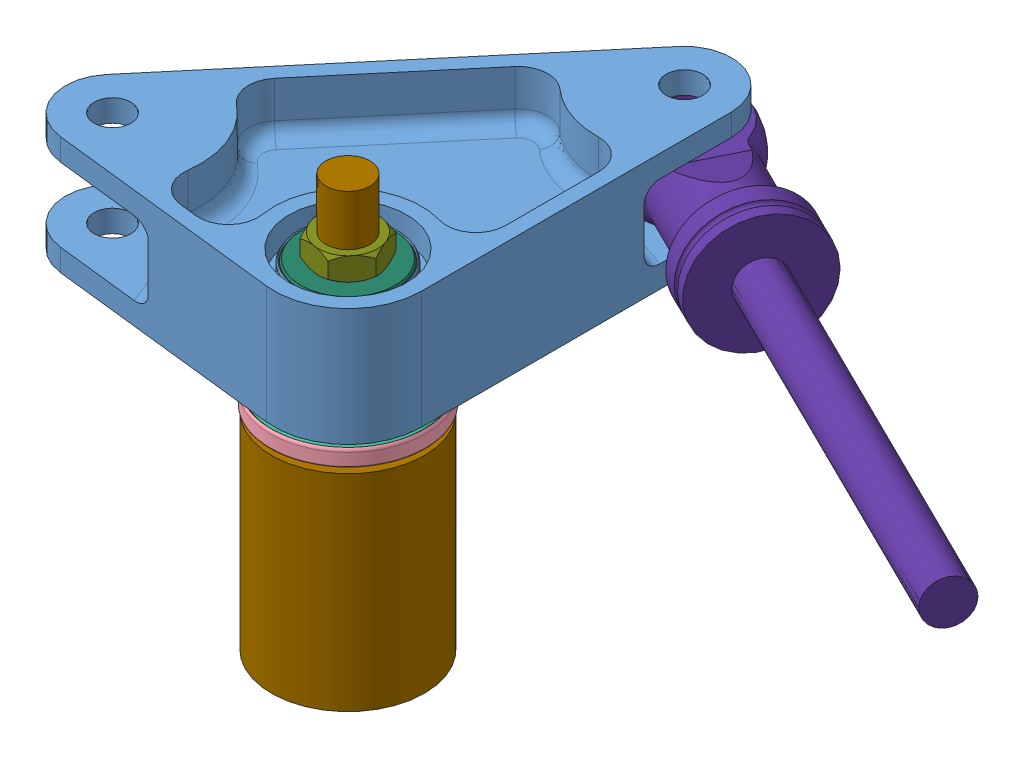
SolidWorks assembly Bell Crank Assembly, configuration Default. Lengths in mm.
Overall size (184.72 88.9 146.21).
20 component instances, 18 part files, 16 mates.
Components (placement in the parent):
- Bell Crank-1: Bell Crank [Default] at origin size (76.83 25.4 92.98)
- combined_bearing_-_rax_718-1: combined_bearing_-_rax_718 [Default] at (0 -16.9 0) x (0 1 0) z (0.807058 0 0.590472) size (18.2 33.5 33.5)
  - combined_bearing_-_rax_718_01-1: combined_bearing_-_rax_718_01 [Default] at origin size (13.9 21.05 21.05)
  - combined_bearing_-_rax_718_02-1: combined_bearing_-_rax_718_02 [Default] at origin size (1.27 30.9 30.9)
  - combined_bearing_-_rax_718_03-1: combined_bearing_-_rax_718_03 [Default] at origin size (3.62 33.5 33.5)
  - combined_bearing_-_rax_718_04-1: combined_bearing_-_rax_718_04 [Default] at origin size (0.66 31.22 31.22)
  - combined_bearing_-_rax_718_05-1: combined_bearing_-_rax_718_05 [Default] at origin size (17.38 32.86 32.86)
  - combined_bearing_-_rax_718_06-1: combined_bearing_-_rax_718_06 [Default] at origin size (11.81 22.36 22.36)
  - combined_bearing_-_rax_718_07-1: combined_bearing_-_rax_718_07 [Default] at origin size (2 28.7 28.7)
- Bell Crank Pivot-1: Bell Crank Pivot [Default] at (0 -55.8 0) x (0 -1 0) z (-0.999995 0 0.003263) size (88.9 33.02 33.02)
- thrust_plate_cp_18_30-2: thrust_plate_cp_18_30 [Default] at (0 -16.9 0) x (0 -1 0) z (0.103205 0 -0.99466) size (0.8 29.5 29.5)
- thrust_plate_cp_10_22-1: thrust_plate_cp_10_22 [Default] at (0 8.1025 0) x (0 -1 0) z (0.860646 0 0.509204) size (0.8 21.5 21.5)
- needles_thrust_bearing_ax_10_22-1: needles_thrust_bearing_ax_10_22 [Default] at (0 10.9025 0) x (0 -1 0) z (-0.277222 0 0.960806) size (2.8 22 22)
  - needles_thrust_bearing_ax_10_22_01-1: needles_thrust_bearing_ax_10_22_01 [Default] at origin size (1.2 20.42 20.42)
  - needles_thrust_bearing_ax_10_22_02-1: needles_thrust_bearing_ax_10_22_02 [Default] at origin size (2 18.6 18.6)
  - needles_thrust_bearing_ax_10_22_03-1: needles_thrust_bearing_ax_10_22_03 [Default] at origin size (2.3 22 22)
  - needles_thrust_bearing_ax_10_22_04-1: needles_thrust_bearing_ax_10_22_04 [Default] at origin size (0.8 21.21 21.21)
- Hex Jam Nut_AI-1: Hex Jam Nut_AI [HJNUT 0.3125-24-D-N] at (0 10.9025 0) x (-0.160393 0 0.987053) z (0 -1 0) size (12.7 14.66 4.95)
- Penske7800_Shaft-1: Penske7800_Shaft [Default] at (5.6801 0 -66.9424) x (0 -1 0) z (0.44263 0 -0.896705) size (25.4 138.11 25.4)
- Inner_Ring_IM_13_18_6.4-2: Inner_Ring_IM_13_18_6.4 [Default] at (0 -8.5 0) x (0 -1 0) z (-0.346095 0 0.938199) size (18.4 18 18)
Mates (geometry in assembly coordinates):
- Concentric1: concentric aligned: cylinder of Bell Crank-1 through (0 2.54 0) axis (0 -1 0) radius 12; cylinder of combined_bearing_-_rax_718-1/combined_bearing_-_rax_718_05-1 through (0 -16.9 0) axis (0 -1 0) radius 12
- Coincident1: coincident anti-aligned: plane of Bell Crank-1 through (-50.8 -12.7 0) normal (0 -1 0); plane of combined_bearing_-_rax_718-1/combined_bearing_-_rax_718_05-1 through (-9.2173 -12.7 12.5982) normal (0 1 0)
- Concentric2: concentric aligned: cylinder of Bell Crank-1 through (0 2.54 0) axis (0 -1 0) radius 12; cylinder of Bell Crank Pivot-1 through (0 -55.8 0) axis (0 -1 0) radius 6.5
- Concentric3: concentric anti-aligned: cylinder of Bell Crank-1 through (0 2.54 0) axis (0 -1 0) radius 12; cylinder of thrust_plate_cp_18_30-2 through (0 -17.7 0) axis (0 1 0) radius 9
- Tangent1: tangent anti-aligned: cylinder of combined_bearing_-_rax_718-1/combined_bearing_-_rax_718_07-1 through (-10.0075 -15.9 -7.3219) axis (0.807058 0 0.590472) radius 1; plane of thrust_plate_cp_18_30-2 through (0 -16.9 0) normal (0 1 0)
- Coincident2: coincident anti-aligned: plane of Bell Crank Pivot-1 through (16.5099 -17.7 -0.0539) normal (0 1 0); plane of thrust_plate_cp_18_30-2 through (0 -17.7 0) normal (0 -1 0)
- Concentric6: concentric anti-aligned: cylinder of Bell Crank Pivot-1 through (0 -55.8 0) axis (0 -1 0) radius 4.7625; cylinder of thrust_plate_cp_10_22-1 through (0 8.1025 0) axis (0 1 0) radius 5
- Coincident4: coincident anti-aligned: plane of Bell Crank-1 through (0 7.3025 0) normal (0 1 0); plane of thrust_plate_cp_10_22-1 through (2.546 7.3025 -4.3032) normal (0 -1 0)
- Concentric7: concentric anti-aligned: cylinder of Bell Crank Pivot-1 through (0 -55.8 0) axis (0 -1 0) radius 4.7625; cylinder of needles_thrust_bearing_ax_10_22-1/needles_thrust_bearing_ax_10_22_04-1 through (0 10.9025 0) axis (0 1 0) radius 5
- Tangent3: tangent anti-aligned: plane of thrust_plate_cp_10_22-1 through (5.4739 8.1025 -9.2519) normal (0 1 0); cylinder of needles_thrust_bearing_ax_10_22-1/needles_thrust_bearing_ax_10_22_02-1 through (-7.3502 9.1025 -2.1207) axis (0.960806 0 0.277222) radius 1
- Concentric8: concentric aligned: cylinder of Bell Crank Pivot-1 through (0 -55.8 0) axis (0 -1 0) radius 4.7625; cylinder of Hex Jam Nut_AI-1 through (0 15.8555 0) axis (0 -1 0) radius 3.4544
- Coincident5: coincident anti-aligned: plane of needles_thrust_bearing_ax_10_22-1/needles_thrust_bearing_ax_10_22_04-1 through (9.7446 10.9025 2.8116) normal (0 1 0); plane of Hex Jam Nut_AI-1 through (-7.2374 10.9025 -1.1761) normal (0 -1 0)
- Concentric11: concentric anti-aligned: circle of Bell Crank-1; cylinder of Penske7800_Shaft-1 through (5.6801 12.7 -66.9424) axis (0 -1 0) radius 7.9375
- Distance2: distance = 1.5875 mm anti-aligned: plane of Bell Crank-1 through (28.0482 7.9375 -72.6581) normal (0 -1 0); plane of Penske7800_Shaft-1 through (39.0513 6.35 -36.3069) normal (0 1 0)
- Tangent4: tangent: plane of Bell Crank Pivot-1 through (16.5099 -17.7 -0.0539) normal (0 1 0); torus of Inner_Ring_IM_13_18_6.4-2
- Concentric12: concentric anti-aligned: cylinder of Bell Crank Pivot-1 through (0 -55.8 0) axis (0 -1 0) radius 6.5; cylinder of Inner_Ring_IM_13_18_6.4-2 through (0 14.8736 0) axis (0 1 0) radius 6.5; sketch_entity of Bell Crank-1
